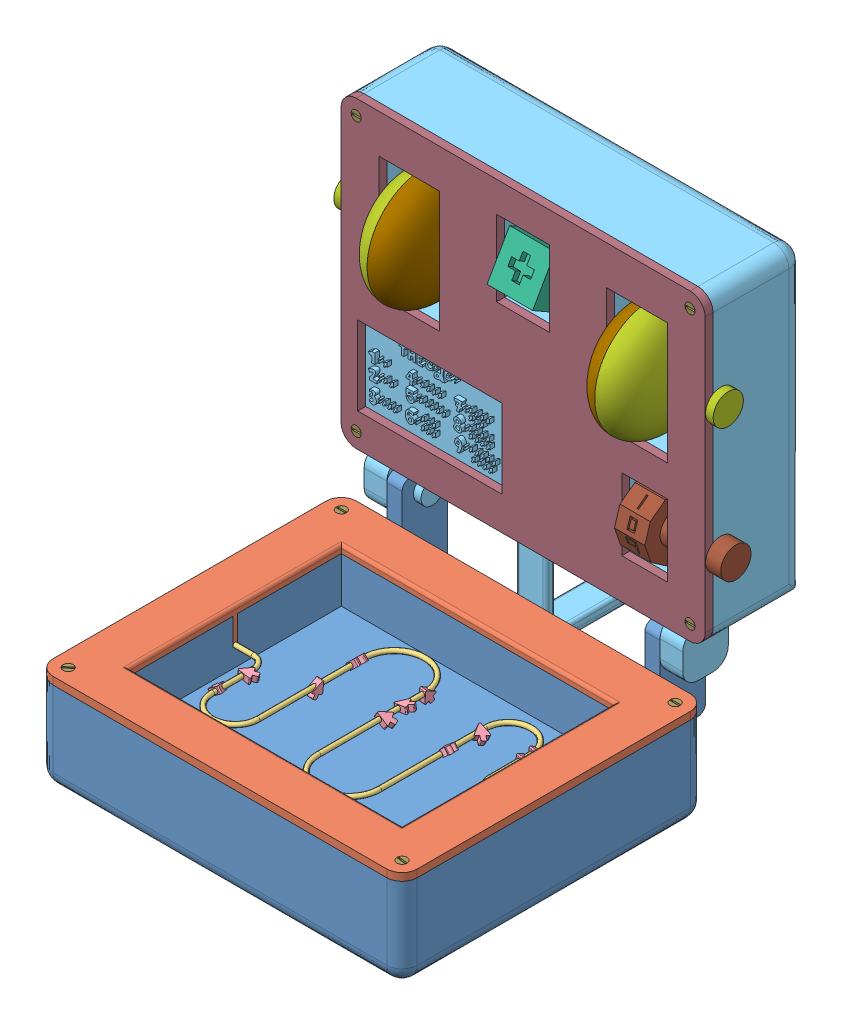
SolidWorks assembly Assem1, configuration Default. Lengths in mm.
Overall size (323.85 374.65 336.55).
34 component instances, 13 part files, 49 mates.
Components (placement in the parent):
- keyboard base-1: keyboard base [Default] at (159.7149 179.1847 166.8086) size (304.8 114.94 292.1)
- Keyboard Top-1: Keyboard Top [Default] at (159.7149 255.3847 166.8086) size (304.8 27.94 254)
- Keyboard Rail-1: Keyboard Rail [Default] at (159.7149 233.7947 166.8086) x (-1 0 0) z (0 1 0) size (254 143.51 3.81)
- Pointer Pieces-1: Pointer Pieces [Default] at (208.7678 229.0537 151.1933) x (-0.068534 -0.056679 -0.996037) z (-0.637311 0.770607 0) size (9.5 11.52 5.08)
- Pointer Pieces-2: Pointer Pieces [Default] at (104.0165 232.5556 133.3407) x (-0.063568 -0.062198 0.996037) z (0.699362 -0.714768 0) size (9.5 11.52 5.08)
- Pointer Pieces-3: Pointer Pieces [Default] at (154.9911 235.588 144.4277) x (-0.087743 -0.014511 0.996037) z (0.163163 -0.986599 0) size (9.5 11.52 5.08)
- Screen Back-1: Screen Back [Default] at (159.7149 426.8347 33.4586) x (1 0 0) z (0 1 0) size (304.8 82.55 330.2)
- Pointer Pieces-4: Pointer Pieces [Default] at (66.9098 237.001 186.5535) x (-0.087789 0.014232 0.996037) z (-0.160027 -0.987113 0) size (9.5 11.52 5.08)
- Pointer Pieces-5: Pointer Pieces [Default] at (157.4885 238.3305 160.3964) x (-0.074009 0.049315 0.996037) z (-0.554511 -0.832177 0) size (9.5 11.52 5.08)
- Pointer Pieces-6: Pointer Pieces [Default] at (205.4815 233.354 124.4967) x (-0.080488 0.03783 -0.996037) z (0.425373 0.905018 0) size (9.5 11.52 5.08)
- Pointer Pieces-7: Pointer Pieces [Default] at (75.8398 234.3233 208.551) x (0.071782 0.052505 0.996037) z (-0.590377 0.807128 0) size (9.5 11.52 5.08)
- Pointer Pieces-8: Pointer Pieces [Default] at (106.7734 238.3712 158.9038) x (0.007909 0.088582 -0.996037) z (0.996037 -0.088935 0) size (9.5 11.52 5.08)
- Pointer Pieces-9: Pointer Pieces [Default] at (251.5333 237.9194 121.7342) x (0.007909 0.088582 0.996037) z (-0.996037 0.088935 0) size (9.5 11.52 5.08)
- Pointer Pieces-10: Pointer Pieces [Default] at (251.5333 237.9194 132.2746) x (0.007909 0.088582 0.996037) z (-0.996037 0.088935 0) size (9.5 11.52 5.08)
- plusminus-1: plusminus [Default] at (159.7149 496.6847 33.4586) x (1 0 0) z (0 -0.495953 -0.868349) size (63.5 38.1 19.05)
- Pointer Pieces-11: Pointer Pieces [Default] at (162.6333 237.9194 124.4258) x (0.007909 0.088582 0.996037) z (-0.996037 0.088935 0) size (9.5 11.52 5.08)
- Spinner_High-1: Spinner_High [Default] at (-4.7672 401.9575 -1.756) x (1 0 0) z (0 0.543457 0.839437) size (127 96.52 96.52)
  - Spinner_Left-1: Spinner_Left [Default] at (69.232 42.5092 61.9063) size (67.95 96.52 96.52)
  - DiceHigh-2: DiceHigh [Default] at (69.2408 8.1247 44.8688) x (0.999999 -0.000781 -0.000912) z (0.0012 0.650573 0.759442) size (12.7 10.41 11)
  - Spinner_Right-1: Spinner_Right [Default] at (69.232 42.5092 61.9063) size (64.49 96.52 96.52)
- Spinner_Low-1: Spinner_Low [Default] at (310.8446 466.3846 108.1444) x (-1 0 0) z (0 -0.440557 -0.897725) size (127 96.52 96.52)
  - Spinner_Left-1: Spinner_Left [Default] at (55.8798 40.0998 70.589) size (67.95 96.52 96.52)
  - DiceLow-1: DiceLow [Default] at (55.8886 5.7153 53.5515) x (0.999999 -0.000781 -0.000912) z (0.0012 0.650573 0.759442) size (12.7 10.41 11)
  - Spinner_Right-1: Spinner_Right [Default] at (55.8798 40.0998 70.589) size (64.49 96.52 96.52)
- Answer_Selector-1: Answer_Selector [Default] at (248.6149 363.3347 27.1086) x (1 0 0) z (0 -0.325605 0.945506) size (101.6 50.8 48.31)
- 92929A163_Nylon Slotted Flat Head Screws (1)-1: 92929A163_Nylon Slotted Flat Head Screws (1) [92929A163] at (20.0149 255.3847 281.1086) x (0.754769 0 -0.655991) z (0 1 0) size (8.32 8.43 12.98)
- 92929A163_Nylon Slotted Flat Head Screws (1)-2: 92929A163_Nylon Slotted Flat Head Screws (1) [92929A163] at (299.4149 255.3847 281.1086) x (0.994636 0 0.103438) z (0 1 0) size (8.32 8.43 12.98)
- 92929A163_Nylon Slotted Flat Head Screws (1)-3: 92929A163_Nylon Slotted Flat Head Screws (1) [92929A163] at (299.4149 255.3847 52.5086) x (1 0 0) z (0 1 0) size (8.32 8.43 12.98)
- 92929A163_Nylon Slotted Flat Head Screws (1)-4: 92929A163_Nylon Slotted Flat Head Screws (1) [92929A163] at (20.0149 255.3847 52.5086) x (1 0 0) z (0 1 0) size (8.32 8.43 12.98)
- ScreenLid-1: ScreenLid [Default] at (159.7149 426.8347 40.0626) x (-1 0 0) z (0 0 -1) size (304.8 254 6.6)
- 92929A163_Nylon Slotted Flat Head Screws (1)-5: 92929A163_Nylon Slotted Flat Head Screws (1) [92929A163] at (20.0149 541.1347 33.7126) size (8.32 8.43 12.98)
- 92929A163_Nylon Slotted Flat Head Screws (1)-6: 92929A163_Nylon Slotted Flat Head Screws (1) [92929A163] at (299.4149 541.1347 33.7126) size (8.32 8.43 12.98)
- 92929A163_Nylon Slotted Flat Head Screws (1)-7: 92929A163_Nylon Slotted Flat Head Screws (1) [92929A163] at (20.0149 312.5347 33.7126) size (8.32 8.43 12.98)
- 92929A163_Nylon Slotted Flat Head Screws (1)-8: 92929A163_Nylon Slotted Flat Head Screws (1) [92929A163] at (299.4149 312.5347 33.7126) size (8.32 8.43 12.98)
Mates (geometry in assembly coordinates):
- Concentric7: concentric anti-aligned: cylinder of Keyboard Rail-1 through (210.5149 233.7947 122.3586) axis (0 0 1) radius 1.905; circle of Pointer Pieces-1
- Concentric8: concentric aligned: cylinder of Keyboard Rail-1 through (108.9149 233.7947 122.3586) axis (0 0 1) radius 1.905; cylinder of Pointer Pieces-2 through (108.9149 233.7947 123.8054) axis (0 0 1) radius 1.905
- Concentric9: concentric anti-aligned: line of Keyboard Rail-1 through (159.7149 233.7947 211.2586) axis (0 0 -1); cylinder of Pointer Pieces-3 through (159.7149 233.7947 134.8924) axis (0 0 1) radius 1.905
- Concentric11: concentric aligned: cylinder of Keyboard Top-1 through (45.4149 233.7947 166.8086) axis (-1 0 0) radius 1.905; cylinder of Keyboard Rail-1 through (60.6549 233.7947 166.8086) axis (-1 0 0) radius 1.905
- Concentric15: concentric anti-aligned: cylinder of Keyboard Rail-1 through (70.8149 233.7947 211.2586) axis (0 0 -1) radius 1.905; cylinder of Pointer Pieces-4 through (70.8149 233.7947 177.0182) axis (0 0 1) radius 1.905
- Concentric16: concentric anti-aligned: cylinder of Keyboard Rail-1 through (210.5149 233.7947 122.3586) axis (0 0 1) radius 1.905; cylinder of Pointer Pieces-6 through (210.5149 233.7947 134.0319) axis (0 0 -1) radius 1.905
- Concentric17: concentric anti-aligned: cylinder of Keyboard Rail-1 through (159.7149 233.7947 211.2586) axis (0 0 -1) radius 1.905; cylinder of Pointer Pieces-5 through (159.7149 233.7947 150.8612) axis (0 0 1) radius 1.905
- Concentric18: concentric anti-aligned: cylinder of Keyboard Rail-1 through (248.6149 233.7947 156.6486) axis (0 0 -1) radius 1.905; cylinder of Pointer Pieces-10 through (248.6149 233.7947 122.7393) axis (0 0 1) radius 1.905
- Concentric19: concentric anti-aligned: cylinder of Keyboard Rail-1 through (248.6149 233.7947 156.6486) axis (0 0 -1) radius 1.905; cylinder of Pointer Pieces-9 through (248.6149 233.7947 112.1989) axis (0 0 1) radius 1.905
- Concentric20: concentric anti-aligned: cylinder of Keyboard Rail-1 through (108.9149 233.7947 122.3586) axis (0 0 1) radius 1.905; cylinder of Pointer Pieces-8 through (108.9149 233.7947 168.439) axis (0 0 -1) radius 1.905
- Concentric21: concentric anti-aligned: cylinder of Keyboard Rail-1 through (70.8149 233.7947 211.2586) axis (0 0 -1) radius 1.905; cylinder of Pointer Pieces-7 through (70.8149 233.7947 199.0157) axis (0 0 1) radius 1.905
- Coincident13: coincident anti-aligned: plane of Screen Back-1 through (191.4649 496.6847 33.4586) normal (-1 0 0); plane of plusminus-1 through (191.4649 496.6847 33.4586) normal (1 0 0)
- Concentric22: concentric anti-aligned: cylinder of Screen Back-1 through (127.9649 496.6847 33.4586) axis (1 0 0) radius 3.175; cylinder of plusminus-1 through (191.4649 496.6847 33.4586) axis (-1 0 0) radius 3.175
- Concentric23: concentric anti-aligned: cylinder of Keyboard Rail-1 through (159.7149 233.7947 211.2586) axis (0 0 -1) radius 1.905; cylinder of Pointer Pieces-11 through (159.7149 233.7947 114.8905) axis (0 0 1) radius 1.905
- Concentric24: concentric aligned: cylinder of keyboard base-1 through (45.4149 233.7947 166.8086) axis (-1 0 0) radius 1.905; cylinder of Keyboard Rail-1 through (60.6549 233.7947 166.8086) axis (-1 0 0) radius 1.905
- Coincident14: coincident anti-aligned: plane of keyboard base-1 through (32.7149 231.8897 164.9036) normal (1 0 0); circle of Keyboard Rail-1
- Concentric25: concentric aligned: cylinder of Keyboard Top-1 through (45.4149 233.7947 166.8086) axis (-1 0 0) radius 1.905; cylinder of Keyboard Rail-1 through (60.6549 233.7947 166.8086) axis (-1 0 0) radius 1.905
- Coincident15: coincident anti-aligned: plane of keyboard base-1 through (32.7149 231.8897 164.9036) normal (1 0 0); plane of Keyboard Top-1 through (32.7149 233.7947 168.7136) normal (-1 0 0)
- Parallel1: parallel anti-aligned: plane of keyboard base-1 through (159.7149 255.3847 166.8086) normal (0 1 0); plane of Keyboard Top-1 through (159.7149 255.3847 166.8086) normal (0 -1 0)
- Coincident17: coincident anti-aligned: plane of Screen Back-1 through (191.4649 471.2847 27.1086) normal (1 0 0); plane of Spinner_Low-1/Spinner_Right-1 through (191.4649 471.2847 27.1086) normal (-1 0 0)
- Concentric26: concentric anti-aligned: circle of Screen Back-1; circle of Spinner_Low-1/Spinner_Right-1
- Concentric27: concentric aligned: cylinder of Screen Back-1 through (127.9649 471.2847 27.1086) axis (-1 0 0) radius 12.7; cylinder of Spinner_High-1/Spinner_Left-1 through (90.5009 471.2847 27.1086) axis (-1 0 0) radius 12.7
- Coincident18: coincident anti-aligned: plane of Screen Back-1 through (127.9649 471.2847 27.1086) normal (-1 0 0); plane of Spinner_High-1/Spinner_Right-1 through (127.9649 471.2847 27.1086) normal (1 0 0)
- Concentric28: concentric aligned: cylinder of Screen Back-1 through (223.2149 363.3347 27.1086) axis (1 0 0) radius 12.7; cylinder of Answer_Selector-1 through (223.2149 363.3347 27.1086) axis (1 0 0) radius 12.7
- Coincident19: coincident anti-aligned: plane of Screen Back-1 through (223.2149 363.3347 27.1086) normal (1 0 0); plane of Answer_Selector-1 through (223.2149 363.3347 27.1086) normal (-1 0 0)
- Concentric30: concentric anti-aligned: cylinder of keyboard base-1 through (20.0149 255.3847 281.1086) axis (0 1 0) radius 1.7272; circle of 92929A163_Nylon Slotted Flat Head Screws-1
- Coincident20: coincident anti-aligned: circle of Keyboard Top-1; circle of 92929A163_Nylon Slotted Flat Head Screws-1
- Concentric31: concentric anti-aligned: circle of keyboard base-1; circle of 92929A163_Nylon Slotted Flat Head Screws-2
- Coincident21: coincident anti-aligned: circle of Keyboard Top-1; circle of 92929A163_Nylon Slotted Flat Head Screws-2
- Concentric32: concentric anti-aligned: circle of keyboard base-1; circle of 92929A163_Nylon Slotted Flat Head Screws-3
- Coincident22: coincident anti-aligned: circle of Keyboard Top-1; circle of 92929A163_Nylon Slotted Flat Head Screws-3
- Concentric33: concentric anti-aligned: circle of keyboard base-1; circle of 92929A163_Nylon Slotted Flat Head Screws-4
- Coincident23: coincident anti-aligned: circle of Keyboard Top-1; circle of 92929A163_Nylon Slotted Flat Head Screws-4
- Coincident24: coincident anti-aligned: plane of Screen Back-1 through (159.7149 426.8347 33.4586) normal (0 0 1); plane of ScreenLid-1 through (159.7149 426.8347 33.4586) normal (0 0 -1)
- Coincident25: coincident aligned: line of Screen Back-1 through (7.3149 312.5347 33.4586) axis (0 1 0); line of ScreenLid-1 through (7.3149 312.5347 33.4586) axis (0 1 0)
- Coincident26: coincident aligned: line of Screen Back-1 through (45.4149 299.8347 33.4586) axis (-1 0 0); line of ScreenLid-1 through (299.4149 299.8347 33.4586) axis (-1 0 0)
- Concentric34: concentric anti-aligned: circle of Screen Back-1; circle of 92929A163_Nylon Slotted Flat Head Screws (1)-5
- Coincident28: coincident anti-aligned: circle of ScreenLid-1; circle of 92929A163_Nylon Slotted Flat Head Screws (1)-5
- Parallel2: parallel aligned: line of ScreenLid-1 through (20.0149 553.8347 40.0626) axis (1 0 0); line of 92929A163_Nylon Slotted Flat Head Screws (1)-5 through (17.2078 540.4405 38.5386) axis (1 0 0)
- Concentric35: concentric anti-aligned: circle of ScreenLid-1; circle of 92929A163_Nylon Slotted Flat Head Screws (1)-6
- Coincident29: coincident anti-aligned: circle of ScreenLid-1; circle of 92929A163_Nylon Slotted Flat Head Screws (1)-6
- Parallel3: parallel aligned: line of ScreenLid-1 through (20.0149 553.8347 40.0626) axis (1 0 0); line of 92929A163_Nylon Slotted Flat Head Screws (1)-6 through (296.6078 540.4405 38.5386) axis (1 0 0)
- Coincident30: coincident anti-aligned: circle of ScreenLid-1; circle of 92929A163_Nylon Slotted Flat Head Screws (1)-8
- Parallel4: parallel anti-aligned: line of ScreenLid-1 through (299.4149 299.8347 40.0626) axis (-1 0 0); line of 92929A163_Nylon Slotted Flat Head Screws (1)-8 through (295.256 311.8405 40.0626) axis (1 0 0)
- Coincident31: coincident anti-aligned: circle of ScreenLid-1; circle of 92929A163_Nylon Slotted Flat Head Screws (1)-7
- Parallel5: parallel anti-aligned: line of ScreenLid-1 through (299.4149 299.8347 40.0626) axis (-1 0 0); line of 92929A163_Nylon Slotted Flat Head Screws (1)-7 through (15.856 311.8405 40.0626) axis (1 0 0)
- Concentric36: concentric anti-aligned: circle of keyboard base (1)-1; circle of Screen Back-1
- Distance1: distance = 6.35 mm: plane of Screen Back-1 through (254.9649 280.7847 20.7586) normal (-1 0 0); line of keyboard base (1)-1 through (261.3149 287.7697 39.8086) axis (0 -1 0)
- LimitAngle1: limit planar angle = 1.570796 rad anti-aligned: plane of ScreenLid-1 through (159.7149 426.8347 40.0626) normal (0 0 1); plane of Keyboard Top (1)-1 through (159.7149 261.7347 166.8086) normal (0 1 0)
